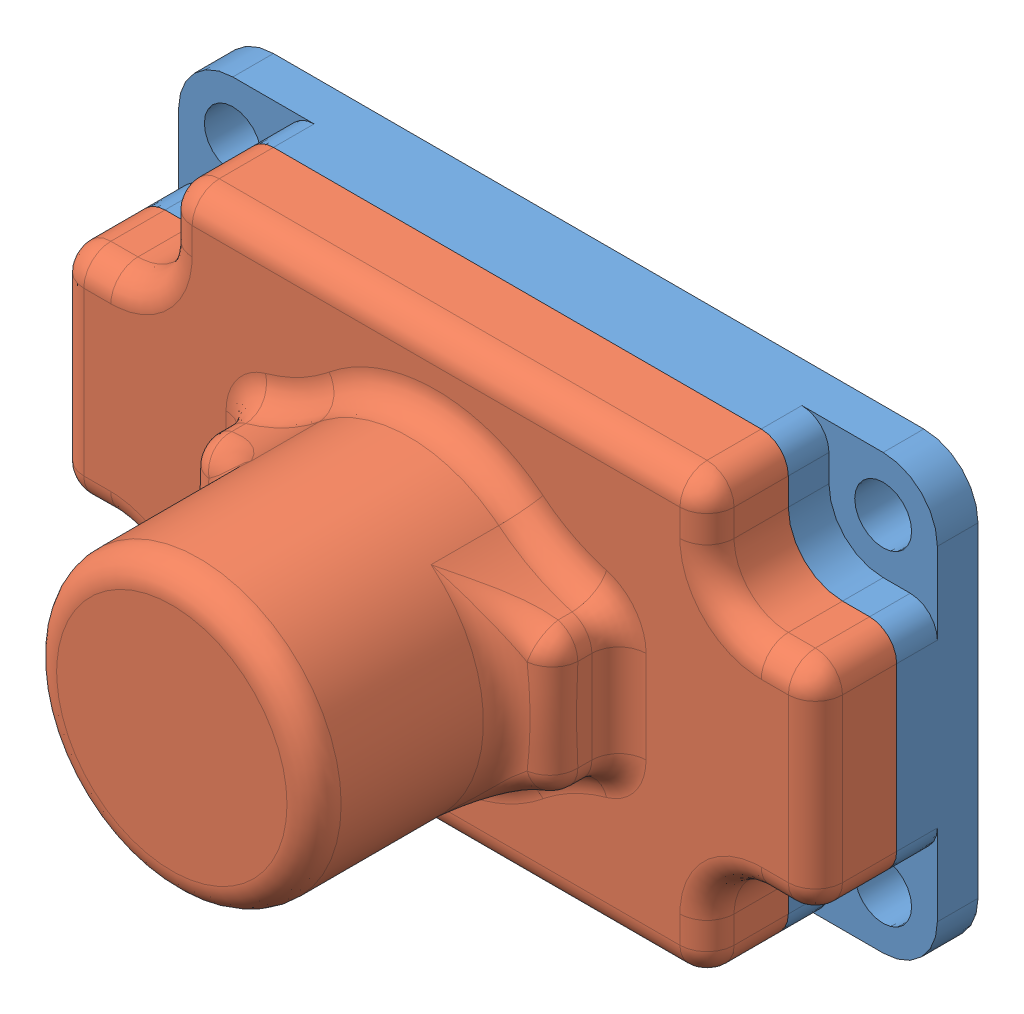
SolidWorks assembly PART_ASSEM_ModernRoboticsLocator, configuration Default. Lengths in mm.
Overall size (56.42 32.42 31.5).
2 component instances, 2 part files, 0 mates.
Components (placement in the parent):
- PART_ASSEM_ModernRoboticsLocator45-0201-1: PART_ASSEM_ModernRoboticsLocator45-0201 [Default] at (-16.4816 -10.3695 -4.5294) size (56 32 6)
- PART_ASSEM_ModernRoboticsLocator45-0217-1: PART_ASSEM_ModernRoboticsLocator45-0217 [Default] at (-16.4816 -10.3695 1.4706) size (56.42 32.42 25.5)
